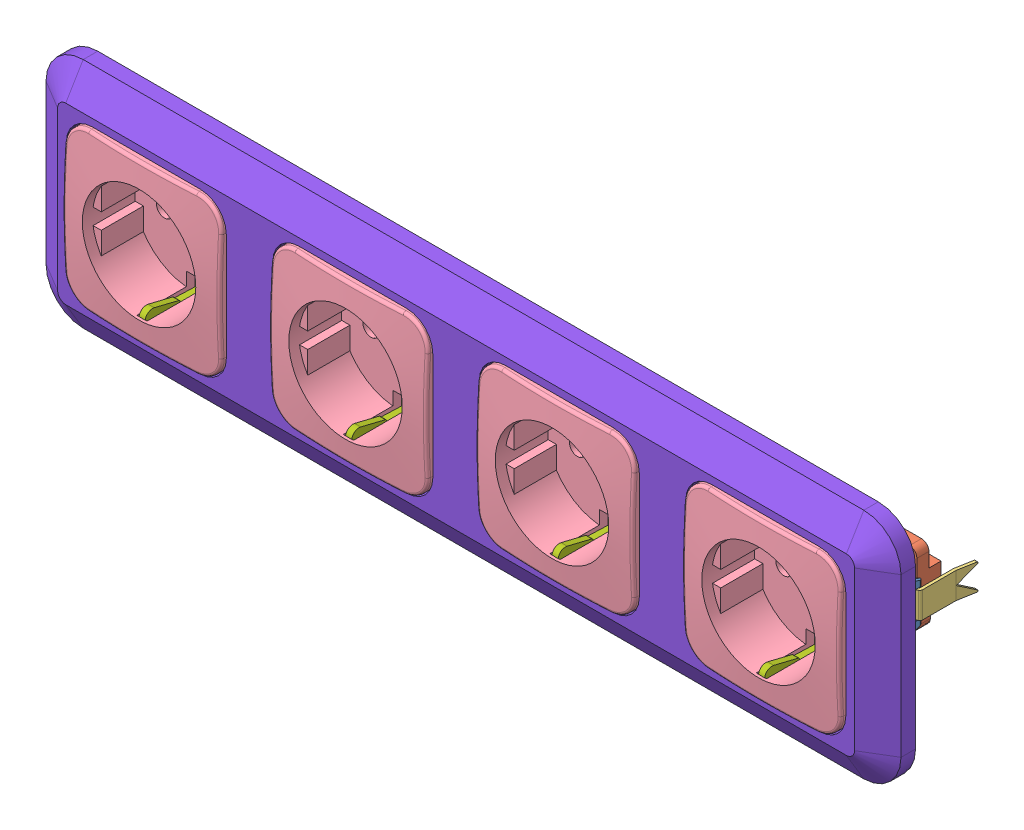
SolidWorks assembly Steckdose_4er, configuration Standard. Lengths in mm.
Overall size (294 80 49.07).
37 component instances, 8 part files, 12 mates.
Components (placement in the parent):
- Steckdose-1: Steckdose [Standard] at (57.8004 112.8398 -124.7318) x (1 0 0) z (0 -1 0) size (71 49.07 71)
  - Montageplatte.02-1: Montageplatte.02 [Standard] at (-76.9981 11 50.9191) x (1 0 0) z (0 1 0) size (71 71 18.97)
  - Halter-1: Halter [Standard] at (-76.9981 11 50.9191) x (1 0 0) z (0 1 0) size (45.97 31.9 15.37)
  - Kralle.04-1: Kralle.04 [Standard] at (-74.3121 12.4168 50.9191) x (0.996195 -0.087156 0) z (0.087156 0.996195 0) size (8.78 9 23.36)
  - Kralle.04-2: Kralle.04 [Standard] at (74.3121 12.4168 -50.9191) x (-0.996195 -0.087156 0) z (-0.087156 0.996195 0) size (8.78 9 23.36)
  - Buchse-1: Buchse [Standard] at (-76.9981 11 50.9191) x (1 0 0) z (0 1 0) size (64.03 64.03 27)
  - Stromklemme_1.02-1: Stromklemme_1.02 [Standard] at (-76.9981 11 50.7921) x (1 0 0) z (0 1 0) size (8.38 19.82 12.51)
  - Stromklemme_2.02-1: Stromklemme_2.02 [Standard] at (-76.9981 11 50.7921) x (1 0 0) z (0 1 0) size (8.38 19.82 12.51)
  - Erdleiter-1: Erdleiter [Standard] at (-76.9981 11 50.9191) x (1 0 0) z (0 1 0) size (7.24 44.01 27.12)
- Steckdose-2: Steckdose [Standard] at (128.8004 112.8398 -124.7318) x (1 0 0) z (0 -1 0) size (71 49.07 71)
  - Montageplatte.02-1: Montageplatte.02 [Standard] at (-76.9981 11 50.9191) x (1 0 0) z (0 1 0) size (71 71 18.97)
  - Halter-1: Halter [Standard] at (-76.9981 11 50.9191) x (1 0 0) z (0 1 0) size (45.97 31.9 15.37)
  - Kralle.04-1: Kralle.04 [Standard] at (-74.3121 12.4168 50.9191) x (0.996195 -0.087156 0) z (0.087156 0.996195 0) size (8.78 9 23.36)
  - Kralle.04-2: Kralle.04 [Standard] at (74.3121 12.4168 -50.9191) x (-0.996195 -0.087156 0) z (-0.087156 0.996195 0) size (8.78 9 23.36)
  - Buchse-1: Buchse [Standard] at (-76.9981 11 50.9191) x (1 0 0) z (0 1 0) size (64.03 64.03 27)
  - Stromklemme_1.02-1: Stromklemme_1.02 [Standard] at (-76.9981 11 50.7921) x (1 0 0) z (0 1 0) size (8.38 19.82 12.51)
  - Stromklemme_2.02-1: Stromklemme_2.02 [Standard] at (-76.9981 11 50.7921) x (1 0 0) z (0 1 0) size (8.38 19.82 12.51)
  - Erdleiter-1: Erdleiter [Standard] at (-76.9981 11 50.9191) x (1 0 0) z (0 1 0) size (7.24 44.01 27.12)
- Wandplatte-1: Wandplatte [4er] at (17.3004 72.8398 -113.7318) size (294 80 11)
- Steckdose-3: Steckdose [Standard] at (270.8004 112.8398 -124.7318) x (1 0 0) z (0 -1 0) size (71 49.07 71)
  - Montageplatte.02-1: Montageplatte.02 [Standard] at (-76.9981 11 50.9191) x (1 0 0) z (0 1 0) size (71 71 18.97)
  - Halter-1: Halter [Standard] at (-76.9981 11 50.9191) x (1 0 0) z (0 1 0) size (45.97 31.9 15.37)
  - Kralle.04-1: Kralle.04 [Standard] at (-74.3121 12.4168 50.9191) x (0.996195 -0.087156 0) z (0.087156 0.996195 0) size (8.78 9 23.36)
  - Kralle.04-2: Kralle.04 [Standard] at (74.3121 12.4168 -50.9191) x (-0.996195 -0.087156 0) z (-0.087156 0.996195 0) size (8.78 9 23.36)
  - Buchse-1: Buchse [Standard] at (-76.9981 11 50.9191) x (1 0 0) z (0 1 0) size (64.03 64.03 27)
  - Stromklemme_1.02-1: Stromklemme_1.02 [Standard] at (-76.9981 11 50.7921) x (1 0 0) z (0 1 0) size (8.38 19.82 12.51)
  - Stromklemme_2.02-1: Stromklemme_2.02 [Standard] at (-76.9981 11 50.7921) x (1 0 0) z (0 1 0) size (8.38 19.82 12.51)
  - Erdleiter-1: Erdleiter [Standard] at (-76.9981 11 50.9191) x (1 0 0) z (0 1 0) size (7.24 44.01 27.12)
- Steckdose-4: Steckdose [Standard] at (199.8004 112.8398 -124.7318) x (1 0 0) z (0 -1 0) size (71 49.07 71)
  - Montageplatte.02-1: Montageplatte.02 [Standard] at (-76.9981 11 50.9191) x (1 0 0) z (0 1 0) size (71 71 18.97)
  - Halter-1: Halter [Standard] at (-76.9981 11 50.9191) x (1 0 0) z (0 1 0) size (45.97 31.9 15.37)
  - Kralle.04-1: Kralle.04 [Standard] at (-74.3121 12.4168 50.9191) x (0.996195 -0.087156 0) z (0.087156 0.996195 0) size (8.78 9 23.36)
  - Kralle.04-2: Kralle.04 [Standard] at (74.3121 12.4168 -50.9191) x (-0.996195 -0.087156 0) z (-0.087156 0.996195 0) size (8.78 9 23.36)
  - Buchse-1: Buchse [Standard] at (-76.9981 11 50.9191) x (1 0 0) z (0 1 0) size (64.03 64.03 27)
  - Stromklemme_1.02-1: Stromklemme_1.02 [Standard] at (-76.9981 11 50.7921) x (1 0 0) z (0 1 0) size (8.38 19.82 12.51)
  - Stromklemme_2.02-1: Stromklemme_2.02 [Standard] at (-76.9981 11 50.7921) x (1 0 0) z (0 1 0) size (8.38 19.82 12.51)
  - Erdleiter-1: Erdleiter [Standard] at (-76.9981 11 50.9191) x (1 0 0) z (0 1 0) size (7.24 44.01 27.12)
Mates (geometry in assembly coordinates):
- Deckungsgleich1: coincident anti-aligned: plane of Steckdose-2/Buchse-1 through (128.8004 81.1649 -113.5126) normal (0 0 -1); plane of Wandplatte-1 through (110.3004 89.1649 -113.5126) normal (0 0 1)
- Deckungsgleich2: coincident anti-aligned: plane of Steckdose-1/Buchse-1 through (57.8004 81.1649 -113.5126) normal (0 0 -1); plane of Wandplatte-1 through (39.3004 89.1649 -113.5126) normal (0 0 1)
- Abstand1: distance = 0.5 mm anti-aligned: plane of Wandplatte-1 through (39.3004 140.3398 -119.7318) normal (0 -1 0); plane of Steckdose-1/Buchse-1 through (39.3004 139.8398 -119.7318) normal (0 1 0)
- Abstand2: distance = 0.5 mm anti-aligned: plane of Steckdose-1/Buchse-1 through (30.8004 94.3398 -119.7318) normal (-1 0 0); plane of Wandplatte-1 through (30.3004 131.3398 -119.7318) normal (1 0 0)
- Abstand3: distance = 0.5 mm anti-aligned: plane of Steckdose-2/Buchse-1 through (110.3004 139.8398 -119.7318) normal (0 1 0); plane of Wandplatte-1 through (110.3004 140.3398 -119.7318) normal (0 -1 0)
- Abstand4: distance = 0.5 mm anti-aligned: plane of Steckdose-2/Buchse-1 through (101.8004 94.3398 -119.7318) normal (-1 0 0); plane of Wandplatte-1 through (101.3004 131.3398 -119.7318) normal (1 0 0)
- Deckungsgleich3: coincident: plane of Wandplatte-1 through (181.3004 94.3398 -119.7318) normal (0 0 1); plane of Steckdose-4/Buchse-1 through (199.8004 86.3398 -119.7318) normal (0 0 -1)
- Deckungsgleich4: coincident: plane of Wandplatte-1 through (252.3004 94.3398 -119.7318) normal (0 0 1); plane of Steckdose-3/Buchse-1 through (270.8004 86.3398 -119.7318) normal (0 0 -1)
- Abstand5: distance = 0.5 mm: plane of Steckdose-4/Buchse-1 through (218.3004 85.8398 -119.7318) normal (0 -1 0); plane of Wandplatte-1 through (181.3004 85.3398 -119.7318) normal (0 1 0)
- Abstand6: distance = 0.5 mm: plane of Wandplatte-1 through (252.3004 85.3398 -119.7318) normal (0 1 0); plane of Steckdose-3/Buchse-1 through (289.3004 85.8398 -119.7318) normal (0 -1 0)
- Abstand7: distance = 0.5 mm anti-aligned: plane of Steckdose-3/Buchse-1 through (297.8004 131.3398 -119.7318) normal (1 0 0); plane of Wandplatte-1 through (298.3004 131.3398 -119.7318) normal (-1 0 0)
- Abstand8: distance = 0.5 mm anti-aligned: plane of Wandplatte-1 through (227.3004 131.3398 -119.7318) normal (-1 0 0); plane of Steckdose-4/Buchse-1 through (226.8004 131.3398 -119.7318) normal (1 0 0)
